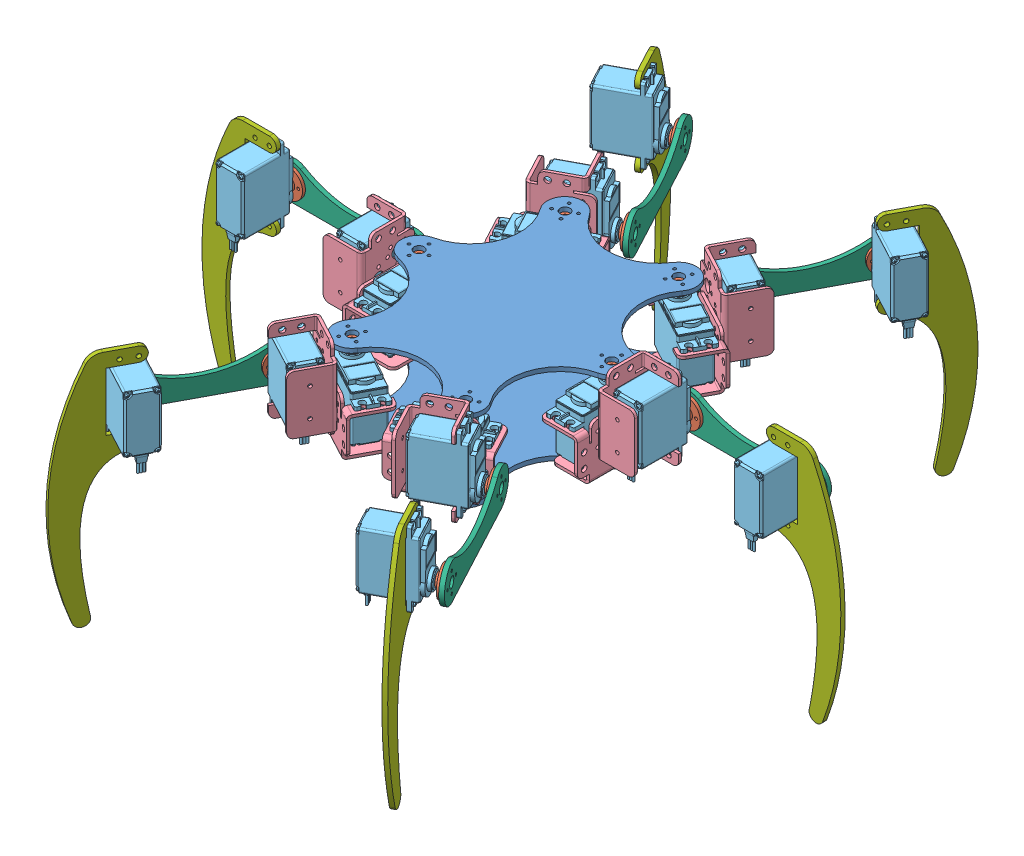
SolidWorks assembly spider, configuration Default. Lengths in mm.
Overall size (450 165.5 458.72).
74 component instances, 7 part files, 40 mates.
Components (placement in the parent):
- body-1: body [Default] at origin size (160.68 3 175)
- horn-1: horn [Default] at (40 0 75) x (-0.470588 0 -0.882353) z (0 -1 0) size (20 20 4.5)
- horn-2: horn [Default] at (-40 0 75) x (-0.470588 0 0.882353) z (0 -1 0) size (20 20 4.5)
- horn-3: horn [Default] at (-67.8388 0 0) x (-1 0 0) z (0 -1 0) size (20 20 4.5)
- horn-4: horn [Default] at (67.8388 0 0) x (-1 0 0) z (0 -1 0) size (20 20 4.5)
- horn-5: horn [Default] at (-40 0 -75) x (-0.470588 0 -0.882353) z (0 -1 0) size (20 20 4.5)
- horn-6: horn [Default] at (40 0 -75) x (-0.470588 0 0.882353) z (0 -1 0) size (20 20 4.5)
- body-2: body [Default] at (0 -54.3 0) size (160.68 3 175)
- left_leg-2: left_leg [Default] at (-67.8388 -2 0) x (1 0 0) z (0 1 0) size (169.29 66.67 165.5) (flexible)
  - bearing-1: bearing [Default] at (0 0 -48.4217) x (0 -1 0) z (0 0 -1) size (9.5 9.5 4)
  - coxa-1: coxa [Défaut] at (-14.87 -10 -48.4217) x (0 -1 0) z (0 0 1) size (58 27 37.5)
  - servo-1: servo [Default] at (9.906 -10.287 -21.3907) x (-1 0 0) z (0 1 0) size (19.81 42.14 58.23)
  - coxa-2: coxa [Défaut] at (-14.87 -25.75 -13.1717) x (0 0 -1) z (0 1 0) size (58 27 37.5)
  - servo-2: servo [Default] at (-19.834 1.281 -12.8847) x (-1 0 0) z (0 0 -1) size (19.81 42.14 58.23)
  - femur-1: femur [Default] at (-72.24 24.6717 -23.1717) x (-1 0 0) z (0 1 0) size (110 25 3)
  - horn-1: horn [Default] at (-114.74 24.6717 -23.1717) x (-1 0 0) z (0 -1 0) size (20 20 4.5)
  - horn-2: horn [Default] at (-29.74 24.6717 -23.1717) x (-1 0 0) z (0 -1 0) size (20 20 4.5)
  - servo-3: servo [Default] at (-104.834 1.281 -12.8847) x (-1 0 0) z (0 0 -1) size (19.81 42.14 58.23)
  - tibia-1: tibia [Default] at (-114.74 4.25 -23.1717) x (0 0 -1) z (0 1 0) size (165.5 56.86 3.1)
- right_leg-1: right_leg [Default] at (40 -2 -75) x (0.470588 0 -0.882353) z (0 1 0) size (169.29 66.67 165.5) (flexible)
  - bearing-1: bearing [Default] at (0 0 -48.4217) x (0.00019 1 0) z (0 0 -1) size (9.5 9.5 4)
  - coxa-1: coxa [Défaut] at (14.87 -10 -48.4217) x (0 1 0) z (0 0 1) size (58 27 37.5)
  - servo-1: servo [Default] at (9.906 -10.287 -21.3907) x (-1 0 0) z (0 1 0) size (19.81 42.14 58.23)
  - coxa-2: coxa [Défaut] at (14.87 -25.75 -13.1717) x (0 0 1) z (0 1 0) size (58 27 37.5)
  - servo-2: servo [Default] at (39.646 1.281 -12.8847) x (-1 0 0) z (0 0 -1) size (19.81 42.14 58.23)
  - femur-1: femur [Default] at (72.24 24.6717 -23.1717) x (-1 0 0) z (0 1 0) size (110 25 3)
  - horn-1: horn [Default] at (29.74 24.6717 -23.1717) x (-1 0 0) z (0 -1 0) size (20 20 4.5)
  - horn-2: horn [Default] at (114.74 24.6717 -23.1717) x (-1 0 0) z (0 -1 0) size (20 20 4.5)
  - servo-3: servo [Default] at (124.646 1.281 -12.8847) x (-1 0 0) z (0 0 -1) size (19.81 42.14 58.23)
  - tibia-1: tibia [Default] at (114.74 7.25 -23.1717) x (0 0 -1) z (0 -1 0) size (165.5 56.86 3.1)
- left_leg-3: left_leg [Default] at (-40 -2 -75) x (0.470588 0 0.882353) z (0 1 0) size (169.29 66.67 165.5) (flexible)
  - bearing-1: bearing [Default] at (0 0 -48.4217) x (0 -1 0) z (0 0 -1) size (9.5 9.5 4)
  - coxa-1: coxa [Défaut] at (-14.87 -10 -48.4217) x (0 -1 0) z (0 0 1) size (58 27 37.5)
  - servo-1: servo [Default] at (9.906 -10.287 -21.3907) x (-1 0 0) z (0 1 0) size (19.81 42.14 58.23)
  - coxa-2: coxa [Défaut] at (-14.87 -25.75 -13.1717) x (0 0 -1) z (0 1 0) size (58 27 37.5)
  - servo-2: servo [Default] at (-19.834 1.281 -12.8847) x (-1 0 0) z (0 0 -1) size (19.81 42.14 58.23)
  - femur-1: femur [Default] at (-72.24 24.6717 -23.1717) x (-1 0 0) z (0 1 0) size (110 25 3)
  - horn-1: horn [Default] at (-114.74 24.6717 -23.1717) x (-1 0 0) z (0 -1 0) size (20 20 4.5)
  - horn-2: horn [Default] at (-29.74 24.6717 -23.1717) x (-1 0 0) z (0 -1 0) size (20 20 4.5)
  - servo-3: servo [Default] at (-104.834 1.281 -12.8847) x (-1 0 0) z (0 0 -1) size (19.81 42.14 58.23)
  - tibia-1: tibia [Default] at (-114.74 4.25 -23.1717) x (0 0 -1) z (0 1 0) size (165.5 56.86 3.1)
- left_leg-4: left_leg [Default] at (-40 -2 75) x (0.470588 0 -0.882353) z (0 1 0) size (169.29 66.67 165.5) (flexible)
  - bearing-1: bearing [Default] at (0 0 -48.4217) x (0 -1 0) z (0 0 -1) size (9.5 9.5 4)
  - coxa-1: coxa [Défaut] at (-14.87 -10 -48.4217) x (0 -1 0) z (0 0 1) size (58 27 37.5)
  - servo-1: servo [Default] at (9.906 -10.287 -21.3907) x (-1 0 0) z (0 1 0) size (19.81 42.14 58.23)
  - coxa-2: coxa [Défaut] at (-14.87 -25.75 -13.1717) x (0 0 -1) z (0 1 0) size (58 27 37.5)
  - servo-2: servo [Default] at (-19.834 1.281 -12.8847) x (-1 0 0) z (0 0 -1) size (19.81 42.14 58.23)
  - femur-1: femur [Default] at (-72.24 24.6717 -23.1717) x (-1 0 0) z (0 1 0) size (110 25 3)
  - horn-1: horn [Default] at (-114.74 24.6717 -23.1717) x (-1 0 0) z (0 -1 0) size (20 20 4.5)
  - horn-2: horn [Default] at (-29.74 24.6717 -23.1717) x (-1 0 0) z (0 -1 0) size (20 20 4.5)
  - servo-3: servo [Default] at (-104.834 1.281 -12.8847) x (-1 0 0) z (0 0 -1) size (19.81 42.14 58.23)
  - tibia-1: tibia [Default] at (-114.74 4.25 -23.1717) x (0 0 -1) z (0 1 0) size (165.5 56.86 3.1)
- right_leg-2: right_leg [Default] at (67.8388 -2 0) x (1 0 0) z (0 1 0) size (169.29 66.67 165.5) (flexible)
  - bearing-1: bearing [Default] at (0 0 -48.4217) x (0.00019 1 0) z (0 0 -1) size (9.5 9.5 4)
  - coxa-1: coxa [Défaut] at (14.87 -10 -48.4217) x (0 1 0) z (0 0 1) size (58 27 37.5)
  - servo-1: servo [Default] at (9.906 -10.287 -21.3907) x (-1 0 0) z (0 1 0) size (19.81 42.14 58.23)
  - coxa-2: coxa [Défaut] at (14.87 -25.75 -13.1717) x (0 0 1) z (0 1 0) size (58 27 37.5)
  - servo-2: servo [Default] at (39.646 1.281 -12.8847) x (-1 0 0) z (0 0 -1) size (19.81 42.14 58.23)
  - femur-1: femur [Default] at (72.24 24.6717 -23.1717) x (-1 0 0) z (0 1 0) size (110 25 3)
  - horn-1: horn [Default] at (29.74 24.6717 -23.1717) x (-1 0 0) z (0 -1 0) size (20 20 4.5)
  - horn-2: horn [Default] at (114.74 24.6717 -23.1717) x (-1 0 0) z (0 -1 0) size (20 20 4.5)
  - servo-3: servo [Default] at (124.646 1.281 -12.8847) x (-1 0 0) z (0 0 -1) size (19.81 42.14 58.23)
  - tibia-1: tibia [Default] at (114.74 7.25 -23.1717) x (0 0 -1) z (0 -1 0) size (165.5 56.86 3.1)
- right_leg-3: right_leg [Default] at (40 -2 75) x (0.470588 0 0.882353) z (0 1 0) size (169.29 66.67 165.5) (flexible)
  - bearing-1: bearing [Default] at (0 0 -48.4217) x (0.00019 1 0) z (0 0 -1) size (9.5 9.5 4)
  - coxa-1: coxa [Défaut] at (14.87 -10 -48.4217) x (0 1 0) z (0 0 1) size (58 27 37.5)
  - servo-1: servo [Default] at (9.906 -10.287 -21.3907) x (-1 0 0) z (0 1 0) size (19.81 42.14 58.23)
  - coxa-2: coxa [Défaut] at (14.87 -25.75 -13.1717) x (0 0 1) z (0 1 0) size (58 27 37.5)
  - servo-2: servo [Default] at (39.646 1.281 -12.8847) x (-1 0 0) z (0 0 -1) size (19.81 42.14 58.23)
  - femur-1: femur [Default] at (72.24 24.6717 -23.1717) x (-1 0 0) z (0 1 0) size (110 25 3)
  - horn-1: horn [Default] at (29.74 24.6717 -23.1717) x (-1 0 0) z (0 -1 0) size (20 20 4.5)
  - horn-2: horn [Default] at (114.74 24.6717 -23.1717) x (-1 0 0) z (0 -1 0) size (20 20 4.5)
  - servo-3: servo [Default] at (124.646 1.281 -12.8847) x (-1 0 0) z (0 0 -1) size (19.81 42.14 58.23)
  - tibia-1: tibia [Default] at (114.74 7.25 -23.1717) x (0 0 -1) z (0 -1 0) size (165.5 56.86 3.1)
Mates (geometry in assembly coordinates):
- Coincident1: coordinate: unknown of body-1
- Concentric1: concentric anti-aligned: cylinder of body-1 through (40 3 75) axis (0 -1 0) radius 3.5; cylinder of horn-1 through (40 -2 75) axis (0 1 0) radius 1.5
- Concentric2: concentric anti-aligned: cylinder of body-1 through (67.8388 3 0) axis (0 -1 0) radius 3.5; cylinder of horn-4 through (67.8388 -2 0) axis (0 1 0) radius 1.5
- Concentric3: concentric anti-aligned: cylinder of body-1 through (40 3 -75) axis (0 -1 0) radius 3.5; cylinder of horn-6 through (40 -2 -75) axis (0 1 0) radius 1.5
- Concentric4: concentric anti-aligned: cylinder of body-1 through (-40 3 -75) axis (0 -1 0) radius 3.5; cylinder of horn-5 through (-40 -2 -75) axis (0 1 0) radius 1.5
- Concentric5: concentric anti-aligned: cylinder of body-1 through (-67.8388 3 0) axis (0 -1 0) radius 3.5; cylinder of horn-3 through (-67.8388 -2 0) axis (0 1 0) radius 1.5
- Concentric6: concentric anti-aligned: cylinder of body-1 through (-40 3 75) axis (0 -1 0) radius 3.5; cylinder of horn-2 through (-40 -2 75) axis (0 1 0) radius 1.5
- Coincident2: coincident anti-aligned: plane of body-1 through (20 0 -87.8087) normal (0 -1 0); plane of horn-2 through (-40 0 75) normal (0 1 0)
- Coincident3: coincident anti-aligned: plane of body-1 through (20 0 -87.8087) normal (0 -1 0); plane of horn-1 through (40 0 75) normal (0 1 0)
- Coincident4: coincident anti-aligned: plane of body-1 through (20 0 -87.8087) normal (0 -1 0); plane of horn-3 through (-67.8388 0 0) normal (0 1 0)
- Coincident5: coincident anti-aligned: plane of body-1 through (20 0 -87.8087) normal (0 -1 0); plane of horn-4 through (67.8388 0 0) normal (0 1 0)
- Coincident6: coincident anti-aligned: plane of body-1 through (20 0 -87.8087) normal (0 -1 0); plane of horn-5 through (-40 0 -75) normal (0 1 0)
- Coincident7: coincident anti-aligned: plane of body-1 through (20 0 -87.8087) normal (0 -1 0); plane of horn-6 through (40 0 -75) normal (0 1 0)
- Concentric7: concentric anti-aligned: cylinder of body-1 through (43.2941 3 81.1765) axis (0 -1 0) radius 1; cylinder of horn-1 through (43.2941 -2 81.1765) axis (0 1 0) radius 1
- Concentric8: concentric anti-aligned: cylinder of body-1 through (74.8388 3 0) axis (0 -1 0) radius 1; cylinder of horn-4 through (74.8388 -2 0) axis (0 1 0) radius 1
- Concentric9: concentric anti-aligned: cylinder of body-1 through (43.2941 3 -81.1765) axis (0 -1 0) radius 1; cylinder of horn-6 through (43.2941 -2 -81.1765) axis (0 1 0) radius 1
- Concentric10: concentric anti-aligned: cylinder of body-1 through (-43.2941 3 -81.1765) axis (0 -1 0) radius 1; cylinder of horn-5 through (-43.2941 -2 -81.1765) axis (0 1 0) radius 1
- Concentric11: concentric anti-aligned: cylinder of body-1 through (-74.8388 3 0) axis (0 -1 0) radius 1; cylinder of horn-3 through (-74.8388 -2 0) axis (0 1 0) radius 1
- Concentric12: concentric anti-aligned: cylinder of body-1 through (-43.2941 3 81.1765) axis (0 -1 0) radius 1; cylinder of horn-2 through (-43.2941 -2 81.1765) axis (0 1 0) radius 1
- Concentric13: concentric aligned: cylinder of body-1 through (0 3 100.6174) axis (0 -1 0) radius 35; cylinder of body-2 through (0 -51.3 100.6174) axis (0 -1 0) radius 35
- Concentric14: concentric aligned: cylinder of body-1 through (0 3 -100.6174) axis (0 -1 0) radius 35; cylinder of body-2 through (0 -51.3 -100.6174) axis (0 -1 0) radius 35
- Distance1: distance = 51.3 mm anti-aligned: plane of body-2 through (20 -51.3 -87.8087) normal (0 1 0); plane of body-1 through (20 0 -87.8087) normal (0 -1 0)
- Coincident21: coincident anti-aligned: plane of horn-3 through (-67.8388 -2 0) normal (0 -1 0); plane of left_leg-2/servo-1 through (-77.7448 -2 10.287) normal (0 1 0)
- Coincident22: coincident anti-aligned: plane of horn-5 through (-40 -2 -75) normal (0 -1 0); plane of left_leg-3/servo-1 through (-53.7384 -2 -78.8996) normal (0 1 0)
- Coincident23: coincident anti-aligned: plane of horn-6 through (40 -2 -75) normal (0 -1 0); plane of right_leg-1/servo-1 through (44.4151 -2 -61.4185) normal (0 1 0)
- Coincident24: coincident anti-aligned: plane of horn-4 through (67.8388 -2 0) normal (0 -1 0); plane of right_leg-2/servo-1 through (57.9328 -2 10.287) normal (0 1 0)
- Coincident25: coincident anti-aligned: plane of horn-1 through (40 -2 75) normal (0 -1 0); plane of right_leg-3/servo-1 through (26.2616 -2 71.1004) normal (0 1 0)
- Coincident26: coincident anti-aligned: plane of horn-2 through (-40 -2 75) normal (0 -1 0); plane of left_leg-4/servo-1 through (-35.5849 -2 88.5815) normal (0 1 0)
- Concentric15: concentric aligned: cylinder of horn-2 through (-40 -2 75) axis (0 1 0) radius 1.5; cylinder of left_leg-4/servo-1 through (-40 -11.6666 75) axis (0 1 0) radius 1.27
- Concentric17: concentric aligned: cylinder of horn-3 through (-67.8388 -2 0) axis (0 1 0) radius 1.5; cylinder of left_leg-2/servo-1 through (-67.8388 -11.6666 0) axis (0 1 0) radius 1.27
- Concentric18: concentric aligned: cylinder of horn-5 through (-40 -2 -75) axis (0 1 0) radius 1.5; cylinder of left_leg-3/servo-1 through (-40 -11.6666 -75) axis (0 1 0) radius 1.27
- Concentric19: concentric aligned: cylinder of horn-6 through (40 -2 -75) axis (0 1 0) radius 1.5; cylinder of right_leg-1/servo-1 through (40 -11.6666 -75) axis (0 1 0) radius 1.27
- Concentric20: concentric aligned: cylinder of horn-4 through (67.8388 -2 0) axis (0 1 0) radius 1.5; cylinder of right_leg-2/servo-1 through (67.8388 -11.6666 0) axis (0 1 0) radius 1.27
- Concentric21: concentric aligned: cylinder of horn-1 through (40 -2 75) axis (0 1 0) radius 1.5; cylinder of right_leg-3/servo-1 through (40 -11.6666 75) axis (0 1 0) radius 1.27
- Coincident13: coordinate: point of horn-3; point of left_leg-2/servo-1
- Coincident14: coordinate: point of horn-5; point of left_leg-3/servo-1
- Coincident15: coordinate: point of horn-2; point of left_leg-4/servo-1
- Coincident17: coordinate: point of horn-6; point of right_leg-1/servo-1
- Coincident18: coordinate: point of horn-4; point of right_leg-2/servo-1
- Coincident19: coordinate: point of horn-1; point of right_leg-3/servo-1
